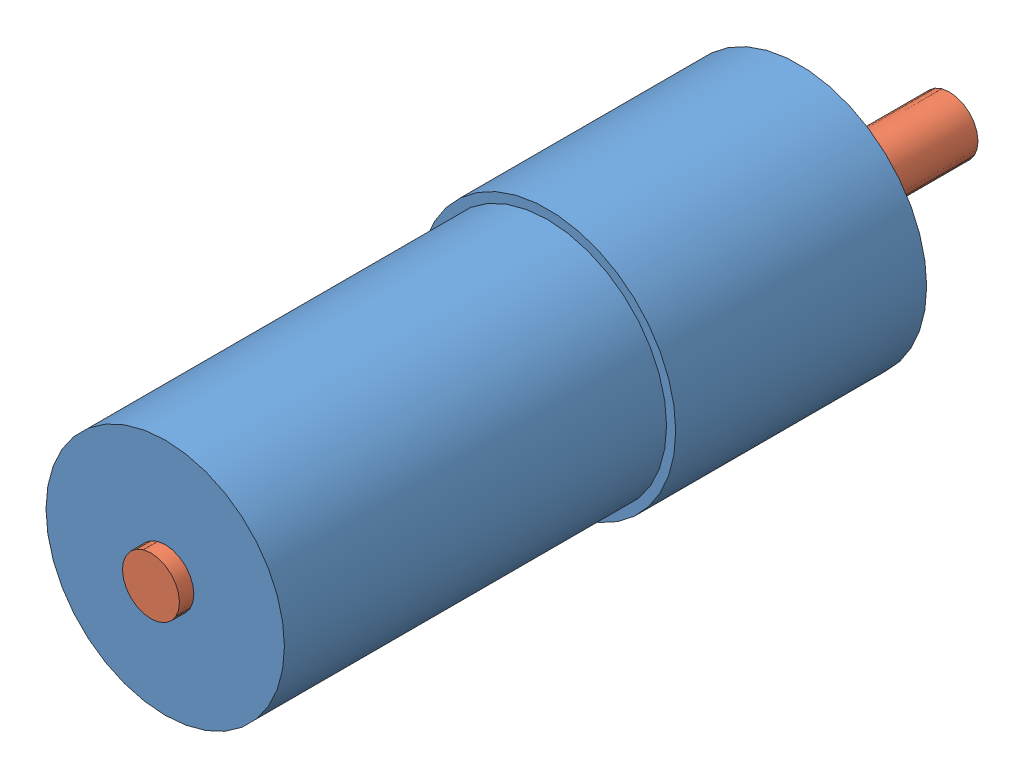
SolidWorks assembly Assem1, configuration Default. Lengths in mm.
Overall size (45 45 140).
2 component instances, 2 part files, 2 mates.
Components (placement in the parent):
- Part1-1: Part1 [Default] at (-43.4482 22.4058 -130.664) size (45 45 113)
- Part2-1: Part2 [Default] at (-43.4482 22.4058 -137.164) x (0.999954 0.009628 0) z (0 0 -1) size (10 10 140)
Mates (geometry in assembly coordinates):
- Concentric1: concentric anti-aligned: cylinder of Part1-1 through (-43.4482 22.4058 40.336) axis (0 0 -1) radius 5.025; cylinder of Part2-1 through (-43.4482 22.4058 -157.164) axis (0 0 1) radius 5
- Distance1: distance = 24.5 mm aligned: plane of Part2-1 through (-43.4482 22.4058 -157.164) normal (0 0 -1); plane of Part1-1 through (-43.4482 22.4058 -132.664) normal (0 0 -1)
